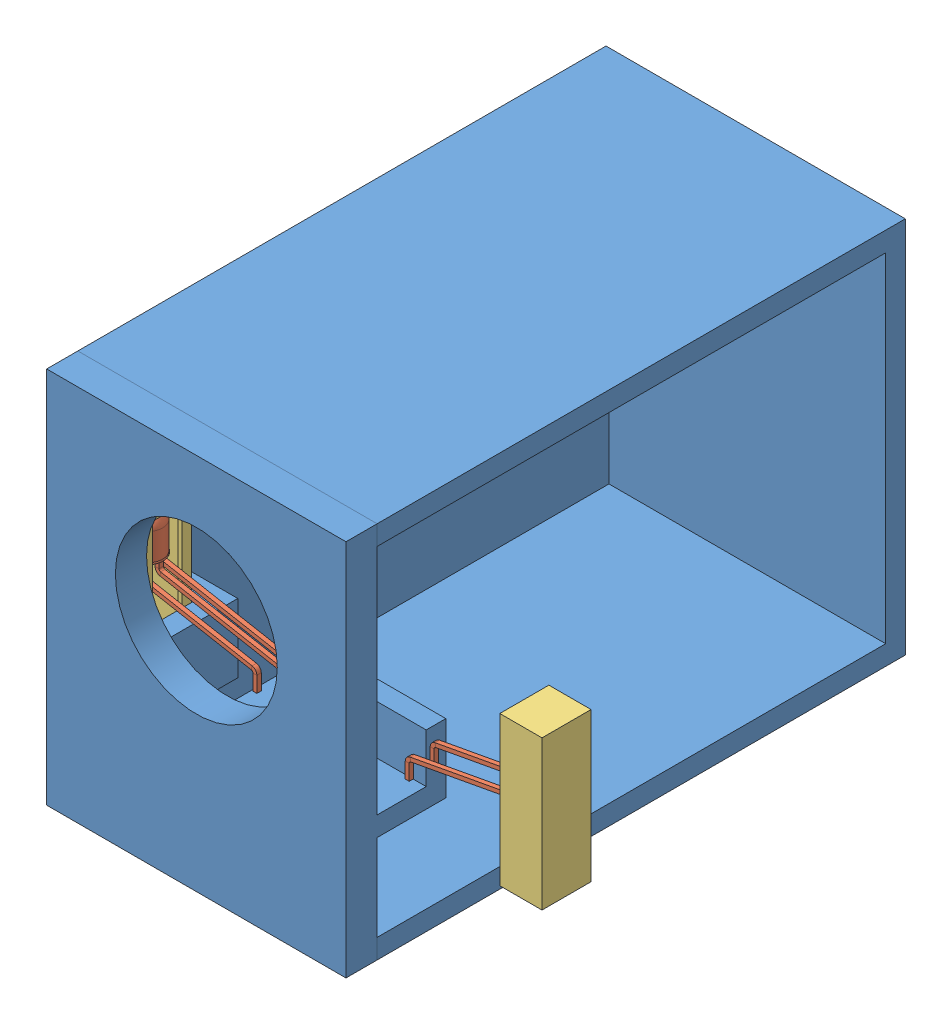
SolidWorks assembly Assem1, configuration Default. Lengths in mm.
Overall size (47.3 38.5 57).
8 component instances, 3 part files, 2 mates.
Components (placement in the parent):
- nosepoke-1: nosepoke [Default] at (1.9893 12.5374 15.1614) size (30.5 38.5 57)
- preferenceV2_dispenser_IRAssembly - Copy-1: preferenceV2_dispenser_IRAssembly - Copy [Default] at (26.9893 27.2874 54.623) x (1 0 -0.000001) z (0.000001 0 1) size (45 15.2 5)
  - sparkfunIR_LEDandCase-1: sparkfunIR_LEDandCase [2Pin] at (-20.5025 21.2786 44.4241) x (-1 0 0) z (0 0 -1) size (14.94 15.2 5)
    - sparkfunIR_LED-1: sparkfunIR_LED [2Pin] at (-40.5025 -12.0786 32.4491) size (14.24 9.86 3.2)
    - sparkfunIR_casing-1: sparkfunIR_casing [Default] at (-40.6525 -5.8286 32.4491) x (1 0 0) z (0 0 -1) size (4.3 15.2 5)
  - sparkfunIR_LEDandCase-2: sparkfunIR_LEDandCase [3Pin] at (20.1025 21.2786 -20.474) x (1 0 0.000001) z (-0.000001 0 1) size (16.44 15.2 5)
    - sparkfunIR_LED-1: sparkfunIR_LED [3Pin] at (-40.5025 -12.0786 32.4491) size (15.74 9.86 3.2)
    - sparkfunIR_casing-1: sparkfunIR_casing [Default] at (-40.6525 -5.8286 32.4491) x (1 0 0) z (0 0 -1) size (4.3 15.2 5)
Mates (geometry in assembly coordinates):
- Coincident10: coincident anti-aligned: line of nosepoke-1 through (4.2893 32.5374 64.098) axis (0 -1 0); line of preferenceV2_dispenser_IRAssembly - Copy-1/sparkfunIR_LEDandCase-2/sparkfunIR_casing-1 through (4.2893 27.5374 64.098) axis (0 1 0)
- Coincident11: coincident aligned: line of preferenceV2_dispenser_IRAssembly - Copy-1/sparkfunIR_LEDandCase-2/sparkfunIR_casing-1 through (4.2893 27.5374 64.098) axis (0 0 1); line of nosepoke-1 through (4.2893 27.5374 64.098) axis (0 0 1)
